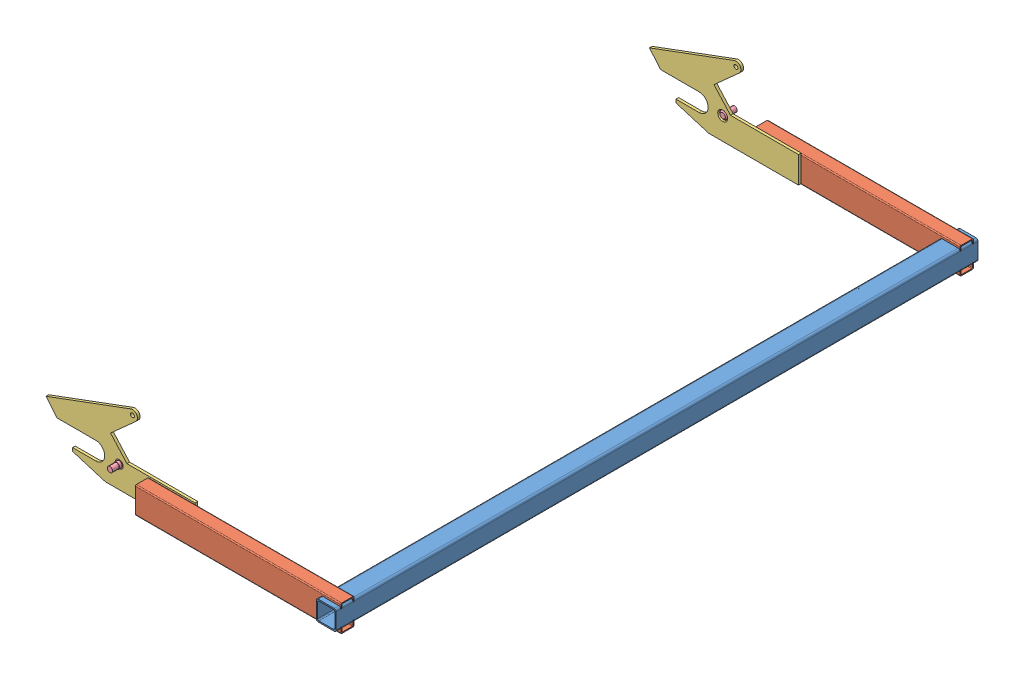
SolidWorks assembly ТП.016.10.01.01.00 - Рама рампы, configuration 00. Lengths in mm.
Overall size (465.09 116.43 969.2).
11 component instances, 4 part files, 6 mates.
Components (placement in the parent):
- ТП.016.10.01.01.01 - Поперечина рампы-1: ТП.016.10.01.01.01 - Поперечина рампы [--] at origin size (30 30 969.2)
- ТП.016.10.01.01.02.00 - Боковина рампы с вилкой-1: ТП.016.10.01.01.02.00 - Боковина рампы с вилкой [Правая] at (-15 -20.75 457.6) x (0 0 -1) z (1 0 0) size (24 116.43 465.09)
  - ТП.016.10.01.01.02.01 - Боковина рампы-1: ТП.016.10.01.01.02.01 - Боковина рампы [--] at origin size (20 40 310)
  - ТП.016.10.01.01.02.02.00 - Вилка замка-1: ТП.016.10.01.01.02.02.00 - Вилка замка [Правая] at (4 35 -360) x (0 0 1) z (-1 0 0) size (225.09 114.93 18)
    - ТП.016.10.01.01.02.02.01 - Вилка навески (Ст3 S4мм)-1: ТП.016.10.01.01.02.02.01 - Вилка навески (Ст3 S4мм) [Правая] at origin size (225.09 114.93 4)
    - ТП.016.10.01.01.02.02.02 - Ось вилки навески-1: ТП.016.10.01.01.02.02.02 - Ось вилки навески [--] at (35.5 0 0) x (0.984194 0.177092 0) z (0 0 1) size (12 12 18)
- ТП.016.10.01.01.02.00 - Боковина рампы с вилкой-2: ТП.016.10.01.01.02.00 - Боковина рампы с вилкой [Левая] at (-15 -20.75 -477.6) x (0 0 -1) z (1 0 0) size (24 116.43 465.09)
  - ТП.016.10.01.01.02.01 - Боковина рампы-1: ТП.016.10.01.01.02.01 - Боковина рампы [--] at origin size (20 40 310)
  - ТП.016.10.01.01.02.02.00 - Вилка замка-1: ТП.016.10.01.01.02.02.00 - Вилка замка [Левая] at (-20 35 -360) x (0 0 1) z (-1 0 0) size (225.09 114.93 18)
    - ТП.016.10.01.01.02.02.01 - Вилка навески (Ст3 S4мм)-1: ТП.016.10.01.01.02.02.01 - Вилка навески (Ст3 S4мм) [Левая] at origin size (225.09 114.93 4)
    - ТП.016.10.01.01.02.02.02 - Ось вилки навески-1: ТП.016.10.01.01.02.02.02 - Ось вилки навески [--] at (35.5 0 4) x (0.984194 -0.177092 0) z (0 0 -1) size (12 12 18)
Mates (geometry in assembly coordinates):
- Совпадение1: coincident: plane of ТП.016.10.01.01.01 - Поперечина рампы-1 through (15 12 527.0264) normal (1 0 0); plane of ТП.016.10.01.01.02.00 - Боковина рампы с вилкой-1/ТП.016.10.01.01.02.01 - Боковина рампы-1 through (15 17.75 459.1) normal (1 0 0)
- Совпадение2: coincident: plane of ТП.016.10.01.01.01 - Поперечина рампы-1 through (-12 15 527.0264) normal (0 1 0); plane of ТП.016.10.01.01.02.00 - Боковина рампы с вилкой-1/ТП.016.10.01.01.02.01 - Боковина рампы-1 through (-12 15 527.0264) normal (0 -1 0)
- Расстояние1: distance = 7 mm: plane of ТП.016.10.01.01.02.00 - Боковина рампы с вилкой-1/ТП.016.10.01.01.02.01 - Боковина рампы-1 through (-409.7214 17.75 477.6) normal (0 0 1); plane of ТП.016.10.01.01.01 - Поперечина рампы-1 through (-409.7214 17.75 484.6) normal (0 0 1)
- Совпадение3: coincident: plane of ТП.016.10.01.01.01 - Поперечина рампы-1 through (15 12 527.0264) normal (1 0 0); plane of ТП.016.10.01.01.02.00 - Боковина рампы с вилкой-2/ТП.016.10.01.01.02.01 - Боковина рампы-1 through (15 17.75 -476.1) normal (1 0 0)
- Совпадение4: coincident: plane of ТП.016.10.01.01.02.00 - Боковина рампы с вилкой-1/ТП.016.10.01.01.02.01 - Боковина рампы-1 through (-409.7214 19.25 476.1) normal (0 1 0); plane of ТП.016.10.01.01.02.00 - Боковина рампы с вилкой-2/ТП.016.10.01.01.02.01 - Боковина рампы-1 through (-409.7214 19.25 -459.1) normal (0 1 0)
- Расстояние2: distance = 7 mm: plane of ТП.016.10.01.01.02.00 - Боковина рампы с вилкой-2/ТП.016.10.01.01.02.01 - Боковина рампы-1 through (-409.7214 17.75 -477.6) normal (0 0 -1); plane of ТП.016.10.01.01.01 - Поперечина рампы-1 through (-409.7214 17.75 -484.6) normal (0 0 -1)
